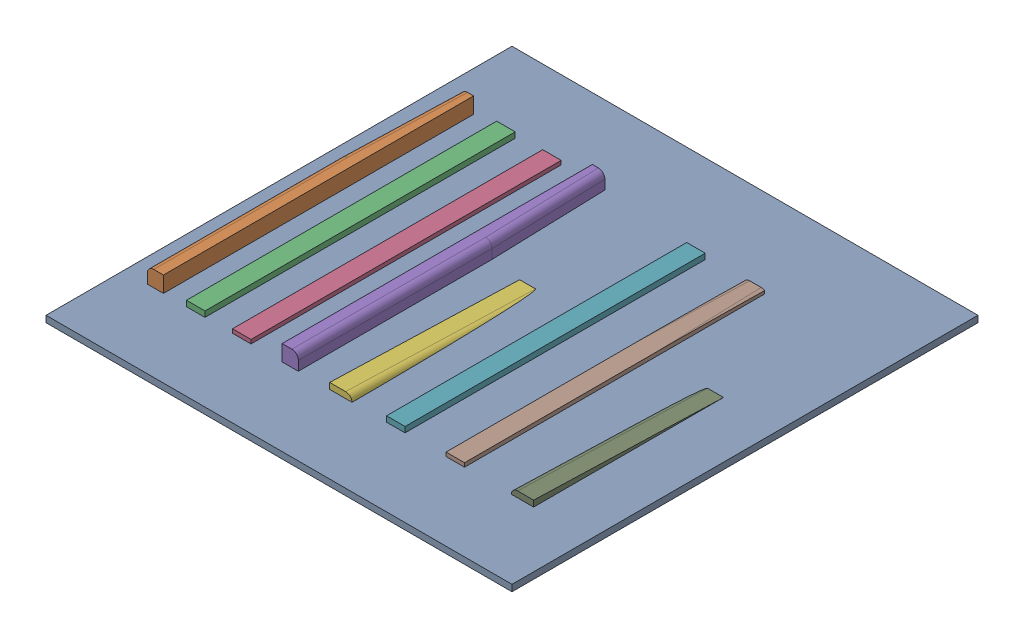
SolidWorks assembly Fuselage Mold_Operation 1, configuration Default. Lengths in mm.
Overall size (758.06 43.94 608.71).
9 component instances, 9 part files, 19 mates.
Components (placement in the parent):
- Cut Area-1: Cut Area [Default] at (0 0 914.4) size (914.4 12.7 914.4) (hidden)
- Fuselage Mold-top-FrontRight-1: Fuselage Mold-top-FrontRight [Default] at (96.2294 -5.969 737.489) size (31.75 43.94 608.71)
- Fuselage Mold-top-FrontBottom-1: Fuselage Mold-top-FrontBottom [Default] at (141.4081 -5.969 737.489) size (36.32 23.62 608.71)
- Fuselage Mold-top-FrontTop-1: Fuselage Mold-top-FrontTop [Default] at (231.7263 -29.591 737.489) size (36.32 20.32 608.71)
- Fuselage Mold-top-frontleft-1: Fuselage Mold-top-frontleft [Default] at (292.8375 -5.969 737.489) size (31.75 43.94 608.71)
- Fuselage Mold-top-BackRight-1: Fuselage Mold-top-BackRight [Default] at (398.3016 -18.161 1346.2) x (0 -1 0) z (0 0 1) size (24.51 43.94 588.97)
- Fuselage Mold-top-BackBottom-1: Fuselage Mold-top-BackBottom [Default] at (534.0157 -5.969 1346.2) size (36.32 23.62 588.97)
- Fuselage Mold-top-BackTop-1: Fuselage Mold-top-BackTop [Default] at (650.7058 -29.591 1346.2) size (36.32 20.32 588.97)
- Fuselage Mold-top-BackLeft-1: Fuselage Mold-top-BackLeft [Default] at (810.3521 -18.161 1346.2) x (0 1 0) z (0 0 1) size (24.51 43.94 588.97)
Mates (geometry in assembly coordinates):
- Coincident1: coincident: point of Cut Area-1
- Parallel1: parallel anti-aligned: plane of Cut Area-1 through (0 12.7 0) normal (0 0 -1)
- Parallel2: parallel anti-aligned: plane of Cut Area-1 through (0 12.7 914.4) normal (-1 0 0)
- Coincident4: coincident aligned: plane of Cut Area-1 through (0 0 914.4) normal (0 -1 0); plane of Fuselage Mold-top-FrontRight-1 through (96.2294 0 737.489) normal (0 -1 0)
- Coincident5: coincident aligned: plane of Cut Area-1 through (0 0 914.4) normal (0 -1 0); plane of Fuselage Mold-top-FrontBottom-1 through (141.4081 0 737.489) normal (0 -1 0)
- Coincident6: coincident aligned: plane of Cut Area-1 through (0 0 914.4) normal (0 -1 0); plane of Fuselage Mold-top-FrontTop-1 through (231.7263 0 737.489) normal (0 -1 0)
- Coincident7: coincident aligned: plane of Cut Area-1 through (0 0 914.4) normal (0 -1 0); plane of Fuselage Mold-top-frontleft-1 through (292.8375 0 737.489) normal (0 -1 0)
- Distance1: distance = 0 mm aligned: plane of Fuselage Mold-top-BackRight-1 through (398.3016 0 1346.2) normal (0 -1 0); plane of Cut Area-1 through (0 0 914.4) normal (0 -1 0)
- Distance2: distance = 0 mm aligned: plane of Fuselage Mold-top-BackBottom-1 through (534.0157 0 1346.2) normal (0 -1 0); plane of Cut Area-1 through (0 0 914.4) normal (0 -1 0)
- Distance3: distance = 0 mm aligned: plane of Fuselage Mold-top-BackTop-1 through (650.7058 0 1346.2) normal (0 -1 0); plane of Cut Area-1 through (0 0 914.4) normal (0 -1 0)
- Distance4: distance = 0 mm aligned: plane of Fuselage Mold-top-BackLeft-1 through (810.3521 0 1346.2) normal (0 -1 0); plane of Cut Area-1 through (0 0 914.4) normal (0 -1 0)
- Distance5: distance = 152.4 mm aligned: plane of Fuselage Mold-top-FrontRight-1 through (96.2294 -5.969 762) normal (0 0 1); plane of Cut Area-1 through (0 12.7 914.4) normal (0 0 1)
- Distance6: distance = 152.4 mm aligned: plane of Fuselage Mold-top-FrontBottom-1 through (141.4081 -5.969 762) normal (0 0 1); plane of Cut Area-1 through (0 12.7 914.4) normal (0 0 1)
- Distance7: distance = 152.4 mm aligned: plane of Fuselage Mold-top-FrontTop-1 through (231.7263 -29.591 762) normal (0 0 1); plane of Cut Area-1 through (0 12.7 914.4) normal (0 0 1)
- Distance8: distance = 152.4 mm aligned: plane of Fuselage Mold-top-frontleft-1 through (292.8375 -5.969 762) normal (0 0 1); plane of Cut Area-1 through (0 12.7 914.4) normal (0 0 1)
- Distance9: distance = 152.4 mm aligned: plane of Fuselage Mold-top-BackRight-1 through (398.3016 -18.161 762) normal (0 0 1); plane of Cut Area-1 through (0 12.7 914.4) normal (0 0 1)
- Distance10: distance = 152.4 mm aligned: plane of Fuselage Mold-top-BackBottom-1 through (534.0157 -5.969 762) normal (0 0 1); plane of Cut Area-1 through (0 12.7 914.4) normal (0 0 1)
- Distance11: distance = 152.4 mm aligned: plane of Fuselage Mold-top-BackTop-1 through (650.7058 -29.591 762) normal (0 0 1); plane of Cut Area-1 through (0 12.7 914.4) normal (0 0 1)
- Distance12: distance = 152.4 mm aligned: plane of Fuselage Mold-top-BackLeft-1 through (810.3521 -18.161 762) normal (0 0 1); plane of Cut Area-1 through (0 12.7 914.4) normal (0 0 1)
